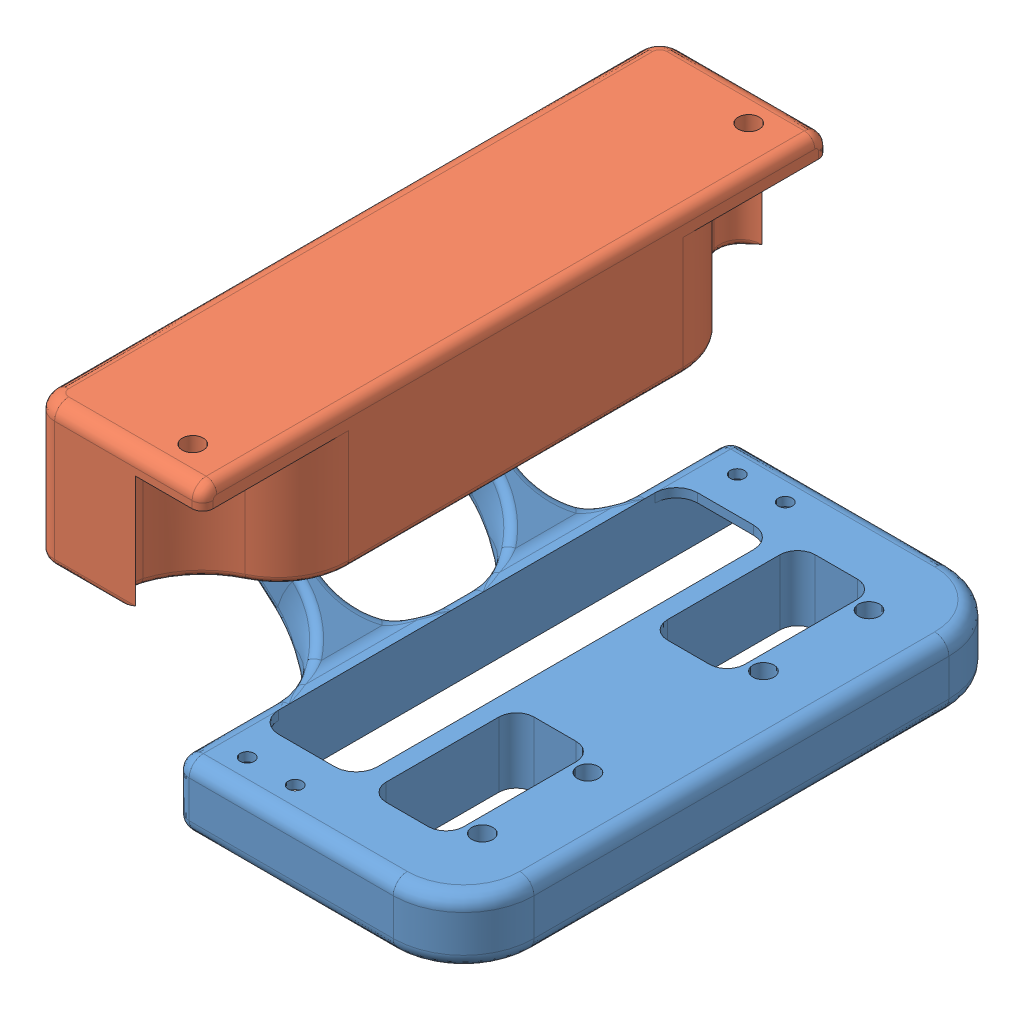
SolidWorks assembly Montagem-Suporte-Sensor, configuration Valor predeterminado. Lengths in mm.
Overall size (66 48.86 89).
2 component instances, 2 part files, 2 mates.
Components (placement in the parent):
- Suporte-Array-Movel (1)-1: Suporte-Array-Movel (1) [Valor predeterminado] at (-27.6262 9.4598 78.95) size (65 25.86 78.95)
- Suporte-Trava-Array-1: Suporte-Trava-Array [Valor predeterminado] at (0.474 32.0324 82.8484) x (0.000123 -1 0) z (0 0 -1) size (30 34.04 89)
Mates (geometry in assembly coordinates):
- Concêntrico2: concentric anti-aligned: circle of Suporte-Array-Movel (1)-1; circle of Suporte-Trava-Array-1
- Distância1: distance = 0.5 mm anti-aligned: plane of Suporte-Trava-Array-1 through (-31.503 32.0284 82.45) normal (0 0 -1); plane of Suporte-Array-Movel (1)-1 through (-27.6262 9.4598 81.95) normal (0 0 1)
